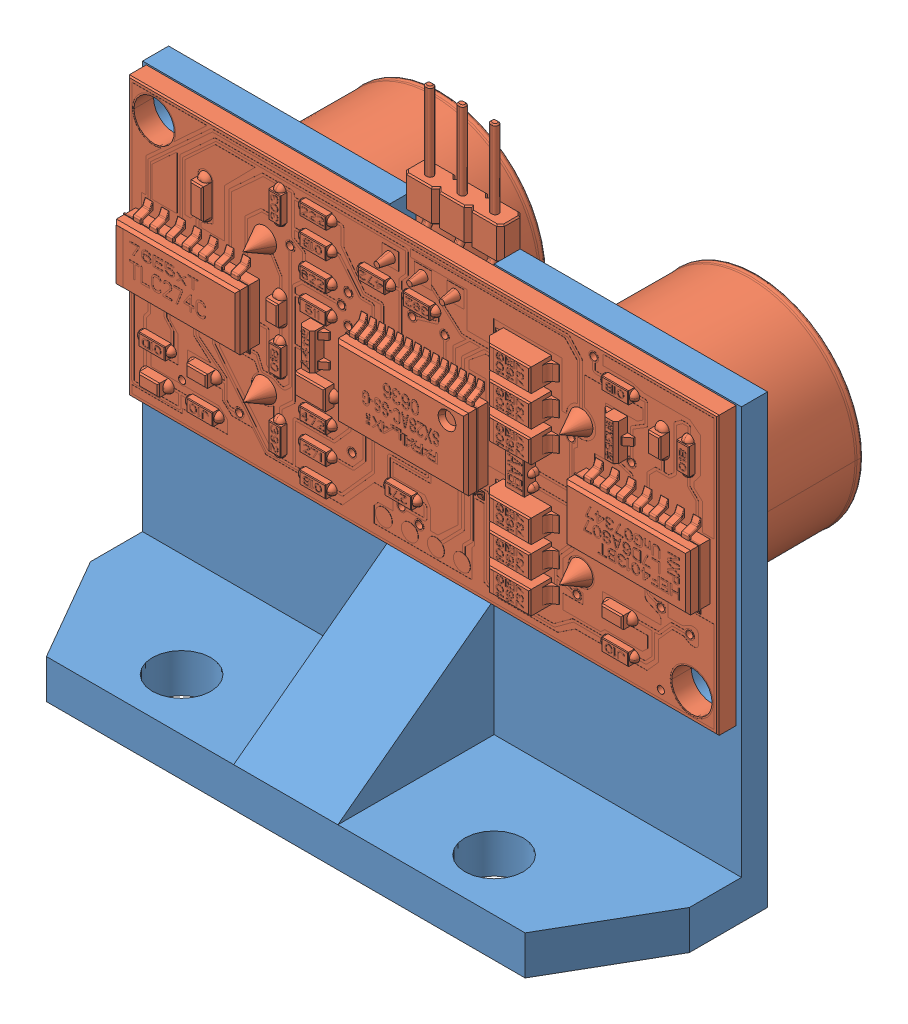
SolidWorks assembly UltraSonic Assembly, configuration 預設. Lengths in mm.
Overall size (46 42.3 23.99).
2 component instances, 2 part files, 4 mates.
Components (placement in the parent):
- Parallax Ping))) Mount-1: Parallax Ping))) Mount [預設] at (6.087 4.4655 39) size (46 34.3 14)
- ping-ultrasonic-range-finder (2019_09_23 07_58_27 UTC).prt-1: ping-ultrasonic-range-finder (2019_09_23 07_58_27 UTC).prt [預設] at (6.137 4.4655 42.5091) x (1 0 0) z (0 0 -1) size (45.3 29.3 15.22)
Mates (geometry in assembly coordinates):
- 同軸心1: concentric: cylinder of Parallax Ping))) Mount-1 through (-6.013 4.4655 39) axis (0 0 1) radius 8.25; cone of ping-ultrasonic-range-finder (2019_09_23 07_58_27 UTC).prt-1 through (-6.013 4.4655 -1828.5057) axis (0 0 -1)
- 平行1: parallel: plane of Parallax Ping))) Mount-1 through (-16.913 -6.1845 41) normal (-1 0 0); plane of ping-ultrasonic-range-finder (2019_09_23 07_58_27 UTC).prt-1 through (-16.513 -6.1845 47.6728) normal (-1 0 0)
- 平行2: parallel: plane of Parallax Ping))) Mount-1 through (-16.913 15.1155 41) normal (0 1 0); plane of ping-ultrasonic-range-finder (2019_09_23 07_58_27 UTC).prt-1 through (-16.513 15.1155 47.6728) normal (0 1 0)
- 重合/共線/共點2: coincident: plane of Parallax Ping))) Mount-1 through (6.087 4.4655 41) normal (0 0 1); plane of ping-ultrasonic-range-finder (2019_09_23 07_58_27 UTC).prt-1 through (1.2377 7.1355 41) normal (0 0 -1)
